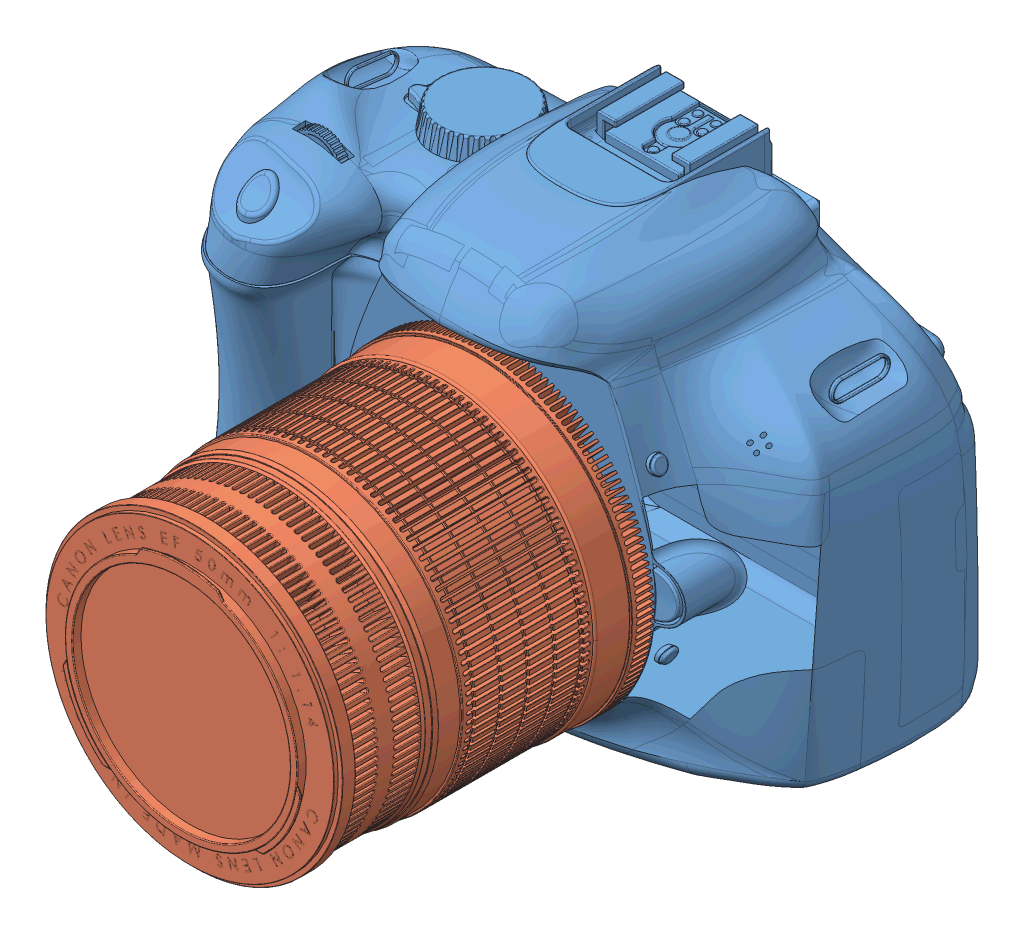
SolidWorks assembly Assembly1, configuration Default. Lengths in mm.
Overall size (135 109.05 139.82).
2 component instances, 2 part files, 0 mates.
Components (placement in the parent):
- body-1: body [Default] at origin size (135 109.05 85.66)
- lens-1: lens [Default] at (0 0 -8) size (71.2 71.2 75.03)
